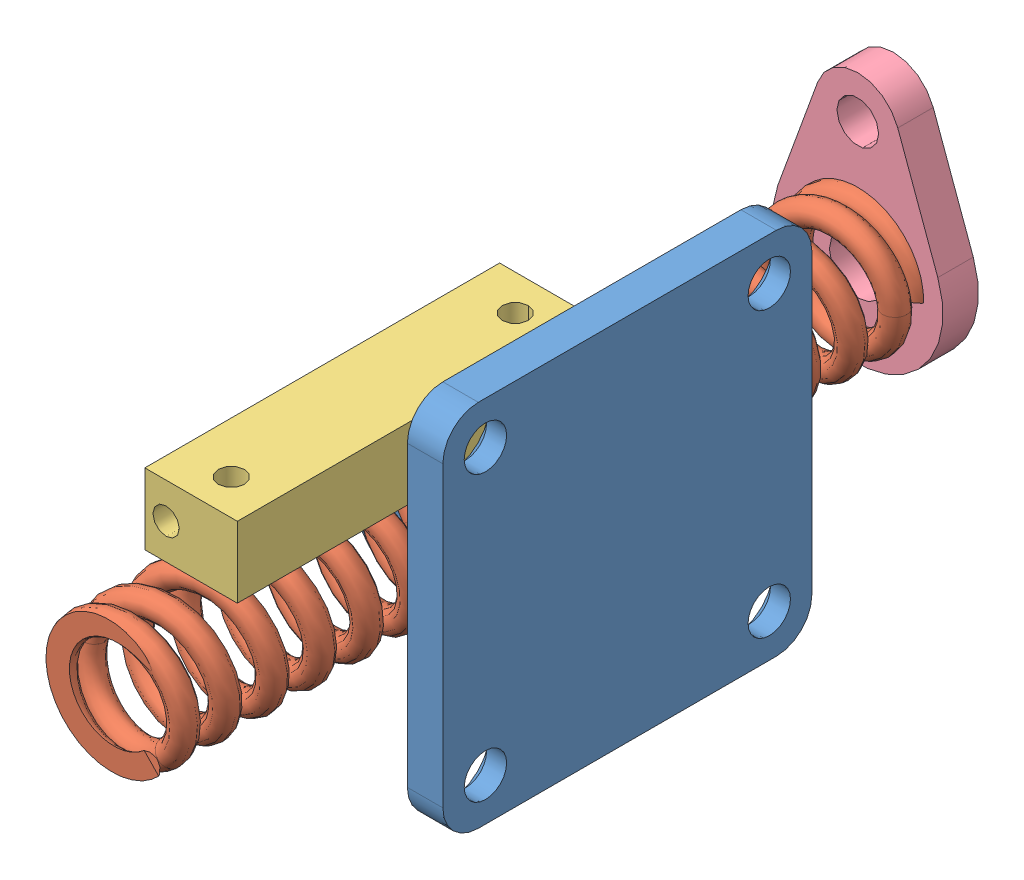
SolidWorks assembly spring-pack-asm, configuration Default. Lengths in mm.
Overall size (20.64 33.02 71.45).
5 component instances, 4 part files, 12 mates.
Components (placement in the parent):
- a06-spring-stop-1: a06-spring-stop [Default] at origin size (20.64 33.02 33.02)
- Lee2E9-1: Lee2E9 [Default] at (-9.525 0 3.2283) size (13.87 13.94 34.98)
- Lee2E9-2: Lee2E9 [Default] at (-9.525 0 -31.6843) size (13.87 13.94 34.98)
- 000_Bourns_linearpot_body_3048seriesRevC-dp2-1: 000_Bourns_linearpot_body_3048seriesRevC-dp2 [Default] at (-11.43 14.2875 -3.175) x (0 0 1) z (1 0 0) size (31.75 6.35 8.28)
- a19-spring-end-stop-shoulder-1: a19-spring-end-stop-shoulder [Default] at (0 0 -33.3251) x (-1 0 0) z (0 0 -1) size (15.24 22.54 3.17)
Mates (geometry in assembly coordinates):
- Concentric1: concentric aligned: cylinder of a06-spring-stop-1; line of Lee2E9-1
- Coincident1: coincident anti-aligned: plane of a06-spring-stop-1 through (-9.525 0 1.5875) normal (0 0 1); plane of Lee2E9-1 through (-9.525 0 1.5875) normal (0 0 -1)
- Coincident2: coincident anti-aligned: plane of a06-spring-stop-1 through (-9.525 0 -1.5875) normal (0 0 -1); plane of Lee2E9-2 through (-9.525 0 -1.5875) normal (0 0 1)
- Coincident3: coincident aligned: line of Lee2E9-1; line of Lee2E9-2
- Parallel1: parallel aligned: plane of a06-spring-stop-1 through (-9.525 7.9375 4.7625) normal (0 1 0); plane of Lee2E9-2 through (-9.525 0 -31.6843) normal (0 1 0)
- Coincident5: coincident aligned: plane of Lee2E9-1 through (-9.525 0 3.2283) normal (1 0 0); plane of Lee2E9-2 through (-9.525 0 -31.6843) normal (1 0 0)
- Concentric2: concentric anti-aligned: cylinder of a06-spring-stop-1; cylinder of 000_Bourns_linearpot_body_3048seriesRevC-dp2-1
- Coincident6: coincident anti-aligned: plane of a06-spring-stop-1 through (-9.525 7.9375 4.7625) normal (0 1 0); plane of 000_Bourns_linearpot_body_3048seriesRevC-dp2-1 through (-3.1496 7.9375 -3.175) normal (0 -1 0)
- Parallel2: parallel anti-aligned: plane of a06-spring-stop-1 through (0 -13.97 16.51) normal (-1 0 0); plane of 000_Bourns_linearpot_body_3048seriesRevC-dp2-1 through (-3.1496 7.9375 -3.175) normal (1 0 0)
- Coincident10: coincident anti-aligned: plane of Lee2E9-2; plane of a19-spring-end-stop-shoulder-1 through (-9.528 11.1125 -33.3251) normal (0 0 1)
- Concentric3: concentric aligned: cylinder of 000_Bourns_linearpot_body_3048seriesRevC-dp2-1; cylinder of a19-spring-end-stop-shoulder-1
- Concentric4: concentric anti-aligned: cylinder of a06-spring-stop-1; cylinder of a19-spring-end-stop-shoulder-1
